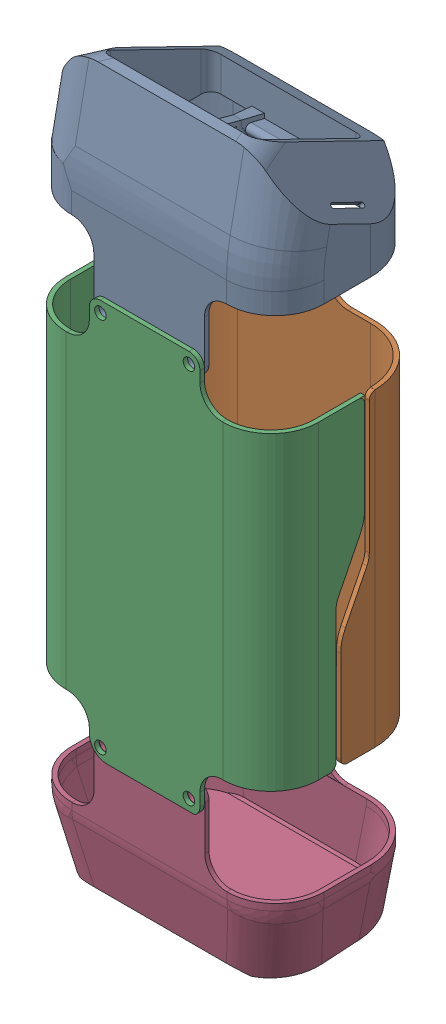
SolidWorks assembly Covers, configuration Default. Lengths in mm.
Overall size (115.6 323.29 74).
4 component instances, 4 part files, 0 mates.
Components (placement in the parent):
- Cover_Nose-1: Cover_Nose [Default] at (291.792 648.6711 914.4489) x (0 1 0) z (0 0 -1) size (93.46 115.6 70.05)
- Cover_Bottom-1: Cover_Bottom [Default] at (1154.1394 1170.0941 1665.8069) x (0 -1 0) z (-1 0 0) size (180 42.4 114)
- Cover_Top-1: Cover_Top [Default] at (1154.1394 -861.2249 -846.2737) x (0 1 0) z (-1 0 0) size (180 42.5 114.01)
- Cover_Rear_Plain-1: Cover_Rear_Plain [Default] at (398.4845 261.595 791.8833) x (0 0 -1) z (0 1 0) size (70.05 114.01 69.83)
